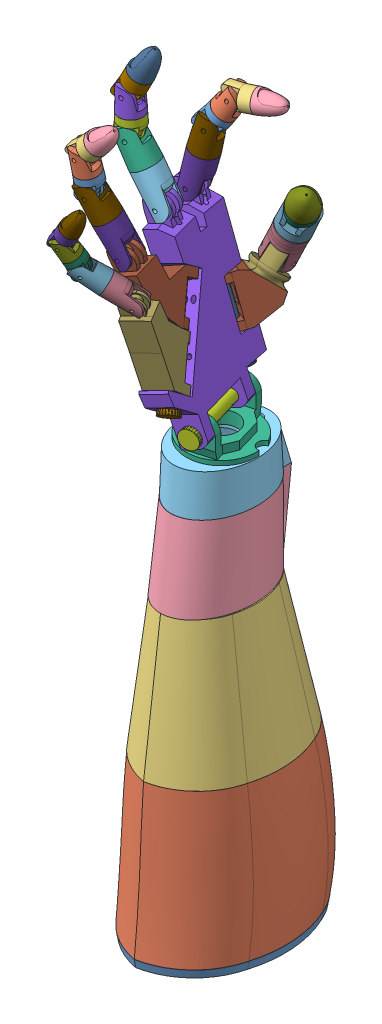
SolidWorks assembly brat bionic_DESEN, configuration Default. Lengths in mm.
Overall size (133.2 492.97 178.43).
47 component instances, 36 part files, 46 mates.
Components (placement in the parent):
- capac-1: capac [Default] x (0 0 1) z (0 -1 0) size (118 85.51 15.8)
- brat-1: brat [Default] at (21.3792 100.51 -54.6588) x (0 0 1) z (0 1 0) size (122.64 91.01 100.55)
- brat3-1: brat3 [Default] at (23.3637 100.51 -0.673) x (0 0 1) z (0 1 0) size (108.18 78.67 92.99)
- rotatie3-1: rotatie3 [Default] at (21.3637 247.6 0.827) x (0 -1 0) z (0 0 -1) size (54.52 53.72 79.07)
- rotatie2-1: rotatie2 [Default] at (21.3637 275.1 2.3667) x (0 0 1) z (0 1 0) size (71.08 50.43 27.52)
- rotatie-1: rotatie [Default] at (21.3637 275.1 0.7767) x (0 1 0) z (-0.279713 0 -0.960084) size (25.5 46.57 47)
- kama3-1: kama3 [Default] at (15.0338 293.6 -20.95) x (0.279713 0 0.960084) z (0.277949 0.957176 -0.080978) size (55.22 12.11 12.06)
- incheietura-1: incheietura [Default] at (-2.942 339.9019 9.4591) x (0.279713 0 0.960084) z (0.902971 0.339759 -0.263073) size (89.87 119.48 17.05)
- kama1-1: kama1 [Default] at (-8.0769 369.6087 -2.1099) x (0.429618 -0.725931 0.537078) z (-0.595277 0.219563 0.772941) size (81.63 11.99 11.99)
- kama2-1: kama2 [Default] at (-9.1071 355.492 -23.8777) x (0.348299 -0.937264 -0.014976) z (-0.570869 -0.224759 0.789679) size (58.94 11.99 11.99)
- deget 1-1: deget 1 [Default] at (-3.3392 333.1412 -37.1218) x (-0.348299 0.937264 0.014976) z (0.814841 0.29483 0.499108) size (30.12 34.69 17)
- deget mare-2: deget mare [Default] at (7.4685 341.2427 -42.0206) x (-0.567496 0.581345 0.583083) z (-0.118243 -0.758362 0.641019) size (43.45 64.19 58.55)
  - deget3-1: deget3 [Default] at origin size (24.28 22.96 17.51)
  - deget 2-1: deget 2 [Default] at (5.185 -11.6868 -28.9168) x (-0.905973 -0.423336 0) z (-0.262459 0.561682 0.78462) size (20 20 23)
  - deget-1: deget [Default] at (9.1429 -20.157 -40.7488) x (-0.262459 0.561682 0.78462) z (0.332158 -0.710844 0.619977) size (15.08 20.32 19.9)
  - Thump50-1: Thump50 [Default] at (12.6343 -27.6289 -42.1434) x (-0.167923 0.359369 -0.917963) z (-0.388607 0.831649 0.396666) size (19.12 18.1 18.16)
  - deget4-1: deget4 [Default] at (12.6343 -27.6289 -42.1434) x (0.905973 0.423336 0) z (-0.167923 0.359369 -0.917963) size (18 20.37 18.06)
- deget ia montaj-1: deget ia montaj [Default] at (-17.3564 410.2511 -26.3348) x (0.955402 -0.189315 -0.226645) z (0.246879 0.090894 0.964774) size (48.75 80.18 17)
  - deget ia 3-4-1: deget ia 3-4 [Default] x (0 0 -1) z (-1 0 0) size (17 27 17)
  - deget ia 3-3-1: deget ia 3-3 [Default] x (0 -1 0) z (-1 0 0) size (22 17 17)
  - deget ia 3-5-1: deget ia 3-5 [Default] at (4.5856 26.5941 0) x (-0.379027 -0.925386 0) z (0 0 -1) size (17.26 16.52 15.41)
  - deget ia 3-6-1: deget ia 3-6 [Default] at (10.6501 41.4003 0) x (-0.379027 -0.925386 0) z (0.925386 -0.379027 0) size (16 15.32 14.93)
  - deget ia 3-2-1: deget ia 3-2 [Default] at (20.2707 40.9559 0) x (-0.328897 0.944366 0) z (-0.944366 -0.328897 0) size (14.75 14.1 18.07)
  - deget ia-1: deget ia [Default] at (20.2694 40.9597 0) x (0 0 1) z (-0.328897 0.944366 0) size (14.02 17.03 14.02)
- deget mijlociu-1: deget mijlociu [Default] at (-24.9915 413.925 5.087) x (0.476461 -0.871782 -0.113937) z (-0.83615 -0.489365 0.247741) size (91.07 17.94 51.58)
  - major3-4-1: major3-4 [Default] x (0 -1 0) z (0 0 1) size (17.93 28.49 17.93)
  - major3-3-1: major3-3 [Default] at origin size (23.21 17.94 17.94)
  - major3-5-1: major3-5 [Default] at (-27.6629 0 -5.8011) x (0.89116 0 0.453688) z (0 -1 0) size (18.44 17.85 16.26)
  - major3-6-1: major3-6 [Default] at (-42.7057 0 -13.4594) x (0.89116 0 0.453688) z (0.453688 0 -0.89116) size (16.88 16.16 15.75)
  - major3-2-1: major3-2 [Default] at (-46.0011 0 -21.6092) x (-0.814988 0 0.579478) z (0.579478 0 0.814988) size (15.56 14.88 19.06)
  - articulatiemijlociu3-1: articulatiemijlociu3 [Default] at (-46.0046 0 -21.6067) x (0 1 0) z (-0.814988 0 0.579478) size (14.79 18.22 14.79)
- incheietura_-1: incheietura_ [Default] at (-2.9717 348.2192 28.4926) x (-0.206102 0.154463 -0.966262) z (0.890728 0.438436 -0.119904) size (37.9 57.51 17.01)
- incheietura2-1: incheietura2 [Default] at (20.6473 360.445 35.269) x (0.399816 0.042041 0.915631) z (-0.887777 -0.230758 0.398249) size (41.78 67.66 17.05)
- articulatie3 montaj-1: articulatie3 montaj [Default] at (2.8426 385.5559 59.6911) x (0.710642 -0.509774 -0.48489) z (-0.545039 -0.834704 0.078746) size (60.35 14.17 42.86)
  - articulatie3-4-1: articulatie3-4 [Default] x (0 -1 0) z (0 0 1) size (14.17 22.51 14.17)
  - articulatie3-3-1: articulatie3-3 [Default] at origin size (18.34 14.17 14.17)
  - articulatie3-5-1: articulatie3-5 [Default] at (-21.6619 0 -4.9815) x (0.870233 0 0.492641) z (0 -1 0) size (14.57 13.77 12.85)
  - articulatie3-6-1: articulatie3-6 [Default] at (-33.2674 0 -11.5513) x (0.870233 0 0.492641) z (0.492641 0 -0.870233) size (13.34 12.77 12.44)
  - articulatie3-2-2: articulatie3-2 [Default] at (-30.6723 0 -19.5986) x (-0.99542 0 0.095597) z (0.095597 0 0.99542) size (12.3 11.75 15.1)
  - articulatie3-1: articulatie3 [Default] at (-30.6757 0 -19.5983) x (0 1 0) z (-0.99542 0 0.095597) size (11.69 14.19 11.69)
- deget ia montaj-2: deget ia montaj [Default] at (-18.6487 402.3542 37.5434) x (0.869334 0.481879 -0.109776) z (0.195105 -0.130536 0.972057) size (48.75 80.18 17)
  - deget ia 3-4-1: deget ia 3-4 [Default] x (0 0 -1) z (-1 0 0) size (17 27 17)
  - deget ia 3-3-1: deget ia 3-3 [Default] x (0 -1 0) z (-1 0 0) size (22 17 17)
  - deget ia 3-5-1: deget ia 3-5 [Default] at (4.5856 26.5941 0) x (-0.379027 -0.925386 0) z (0 0 -1) size (17.26 16.52 15.41)
  - deget ia 3-6-1: deget ia 3-6 [Default] at (10.6501 41.4003 0) x (-0.379027 -0.925386 0) z (0.925386 -0.379027 0) size (16 15.32 14.93)
  - deget ia 3-2-1: deget ia 3-2 [Default] at (20.2707 40.9559 0) x (-0.328897 0.944366 0) z (-0.944366 -0.328897 0) size (14.75 14.1 18.07)
  - deget ia-1: deget ia [Default] at (20.2694 40.9597 0) x (0 0 1) z (-0.328897 0.944366 0) size (14.02 17.03 14.02)
Mates (geometry in assembly coordinates):
- Coincident1: coincident anti-aligned: plane of capac-1 through (0 0 0) normal (0 -1 0)
- Coincident2: coincident anti-aligned: plane of capac-1 through (0 0 0) normal (-1 0 0)
- Coincident3: coincident aligned: plane of capac-1 through (0 0 0) normal (0 0 1)
- Concentric8: concentric aligned: circle of capac-1; circle of brat-1
- Coincident4: coincident anti-aligned: plane of capac-1 through (27.0674 0 -14.9828) normal (0 1 0); plane of brat-1 through (12.3179 0 10.0833) normal (0 -1 0)
- Parallel1: parallel aligned: plane of brat-1 through (21.3792 100.51 -54.6588) normal (1 0 0)
- Concentric10: concentric aligned: circle of brat-1; circle of brat3-1
- Coincident5: coincident anti-aligned: plane of brat-1 through (16.2073 100.51 -14.3784) normal (0 1 0); plane of brat3-1 through (15.3542 100.51 -13.3417) normal (0 -1 0)
- Parallel2: parallel aligned: plane of brat-1 through (21.3792 100.51 -54.6588) normal (1 0 0); plane of brat3-1 through (23.3637 100.51 -0.673) normal (1 0 0)
- Distance5: distance = 2 mm anti-aligned: plane of brat3-1 through (23.3637 100.51 -0.673) normal (1 0 0); plane of rotatie3-1 through (21.3637 247.6 0.827) normal (-1 0 0)
- Coincident7: coincident anti-aligned: plane of brat3-1 through (17.2122 193.1 -4.2925) normal (0 1 0); plane of rotatie3-1 through (21.3637 193.1 4.397) normal (0 -1 0)
- Distance6: distance = 1.5 mm anti-aligned: plane of rotatie3-1 through (21.3637 247.6 0.827) normal (0 0 -1); plane of brat3-1 through (23.3637 100.51 -0.673) normal (0 0 1)
- Coincident9: coincident anti-aligned: plane of rotatie3-1 through (21.3637 247.6 0.827) normal (0 1 0); plane of rotatie2-1 through (21.4437 247.6 0.7167) normal (0 -1 0)
- Coincident10: coincident anti-aligned: line of rotatie3-1 through (10.5337 247.6 -35.6949) axis (1 0 0); line of rotatie2-1 through (32.1137 247.6 -35.6949) axis (-1 0 0)
- Coincident12: coincident anti-aligned: plane of rotatie3-1 through (21.3637 247.6 0.827) normal (-1 0 0); plane of rotatie2-1 through (21.3637 275.1 2.3667) normal (1 0 0)
- Concentric11: concentric anti-aligned: cylinder of rotatie2-1; cylinder of rotatie-1 through (21.3637 278.1 0.7767) axis (0 -1 0) radius 10.75
- Coincident14: coincident anti-aligned: plane of rotatie2-1 through (21.3637 275.1 0.7767) normal (0 1 0); plane of rotatie-1 through (32.6447 275.1 -2.5099) normal (0 -1 0)
- Concentric12: concentric aligned: cylinder of rotatie-1 through (30.8582 293.6 33.3655) axis (-0.279713 0 -0.960084) radius 4; cylinder of kama3-1 through (29.6181 293.6 29.1088) axis (-0.279713 0 -0.960084) radius 4
- Coincident15: coincident anti-aligned: circle of kama3-1; plane of rotatie-1 through (23.9962 300.6 -23.5611) normal (-0.279713 0 -0.960084)
- Concentric13: concentric aligned: cylinder of kama3-1 through (29.6181 293.6 29.1088) axis (-0.279713 0 -0.960084) radius 4; cylinder of incheietura-1 through (32.7826 293.6 39.9709) axis (-0.279713 0 -0.960084) radius 4
- Coincident16: coincident anti-aligned: plane of rotatie-1 through (36.656 300.6 19.8923) normal (0.279713 0 0.960084); plane of incheietura-1 through (32.3055 305.3204 21.1598) normal (-0.279713 0 -0.960084)
- LimitAngle2: limit planar angle = 0.444162 rad aligned: plane of incheietura-1 through (-2.942 339.9019 9.4591) normal (0.902971 0.339759 -0.263073)
- Concentric14: concentric anti-aligned: cylinder of incheietura-1 through (-8.3833 370.1265 -2.493) axis (0.429618 -0.725931 0.537078) radius 4; cylinder of kama1-1 through (25.704 312.5287 40.1205) axis (-0.429618 0.725931 -0.537078) radius 4
- Coincident17: coincident anti-aligned: plane of incheietura-1 through (33.2749 308.0741 28.0434) normal (0.429618 -0.725931 0.537078); plane of kama1-1 through (25.704 312.5287 40.1205) normal (-0.429618 0.725931 -0.537078)
- Concentric15: concentric anti-aligned: cylinder of incheietura-1 through (-9.0861 355.4355 -23.8786) axis (0.348299 -0.937264 -0.014976) radius 4; cylinder of kama2-1 through (10.3768 303.0614 -24.7154) axis (-0.348299 0.937264 0.014976) radius 4
- Coincident18: coincident anti-aligned: plane of incheietura-1 through (15.8878 305.2777 -35.2476) normal (0.348299 -0.937264 -0.014976); plane of kama2-1 through (10.3768 303.0614 -24.7154) normal (-0.348299 0.937264 0.014976)
- Concentric16: concentric aligned: cylinder of kama2-1 through (10.3768 303.0614 -24.7154) axis (-0.348299 0.937264 0.014976) radius 4; cylinder of deget 1-1 through (6.4434 313.6459 -24.5463) axis (-0.348299 0.937264 0.014976) radius 4
- Symmetric1: symmetric aligned: plane of deget 1-1 through (5.1437 350.6115 -27.23) normal (-0.348299 0.937264 0.014976); plane of deget 1-1 through (8.683 319.5923 -14.6849) normal (0.348299 -0.937264 -0.014976)
- Coincident20: coincident anti-aligned: plane of deget 1-1 through (20.7171 336.9896 -44.6084) normal (0.118243 0.758362 -0.641019); plane of deget mare-2/deget3-1 through (7.4685 341.2427 -42.0206) normal (-0.118243 -0.758362 0.641019)
- Coincident21: coincident aligned: line of deget 1-1 through (20.7171 336.9896 -44.6084) axis (-0.567496 0.581345 0.583083); line of deget mare-2/deget3-1 through (20.7171 336.9896 -44.6084) axis (-0.567496 0.581345 0.583083)
- Coincident22: coincident anti-aligned: line of deget 1-1 through (20.7171 336.9896 -44.6084) axis (-0.814841 -0.29483 -0.499108); line of deget mare-2/deget3-1 through (6.8648 331.9774 -53.0933) axis (0.814841 0.29483 0.499108)
- Concentric17: concentric anti-aligned: cylinder of incheietura-1 through (-1.2977 397.8308 55.7071) axis (-0.246879 -0.090894 -0.964774) radius 1.25; cylinder of deget ia montaj-1/deget ia 3-4-1 through (-28.2044 387.9246 -49.4412) axis (0.246879 0.090894 0.964774) radius 1.25
- Coincident23: coincident anti-aligned: plane of incheietura-1 through (-17.1844 397.3683 -29.8294) normal (-0.246879 -0.090894 -0.964774); plane of deget ia montaj-1/deget ia 3-4-1 through (-10.3454 408.2327 -32.603) normal (0.246879 0.090894 0.964774)
- Concentric18: concentric aligned: cylinder of incheietura-1 through (-14.1898 394.7138 7.4306) axis (0.271733 0.02277 0.962103) radius 1.25; cylinder of deget mijlociu-1/major3-4-1 through (-23.2215 393.957 -24.5473) axis (0.271733 0.02277 0.962103) radius 1.3188
- Coincident24: coincident anti-aligned: plane of incheietura-1 through (-11.2119 401.9167 -3.4551) normal (-0.271733 -0.02277 -0.962103); plane of deget mijlociu-1/major3-4-1 through (-18.7825 418.2058 -1.7024) normal (0.271733 0.02277 0.962103)
- Coincident25: coincident anti-aligned: plane of incheietura-1 through (3.5372 362.1672 -4.1671) normal (0.429618 -0.725931 0.537078); plane of incheietura_-1 through (1.4862 373.7264 13.0973) normal (-0.429618 0.725931 -0.537078)
- Concentric19: concentric aligned: cylinder of kama1-1 through (25.704 312.5287 40.1205) axis (-0.429618 0.725931 -0.537078) radius 4; cylinder of incheietura_-1 through (13.9737 332.3495 25.4562) axis (-0.429618 0.725931 -0.537078) radius 4
- Concentric20: concentric anti-aligned: cylinder of kama1-1 through (25.704 312.5287 40.1205) axis (-0.429618 0.725931 -0.537078) radius 4; cylinder of incheietura2-1 through (5.3645 346.8967 14.6935) axis (0.429618 -0.725931 0.537078) radius 4
- Coincident26: coincident anti-aligned: plane of incheietura-1 through (30.3444 329.1909 45.2571) normal (-0.429618 0.725931 -0.537078); plane of incheietura2-1 through (17.3204 324.988 49.9945) normal (0.429618 -0.725931 0.537078)
- Concentric21: concentric aligned: cylinder of incheietura2-1 through (11.6796 377.5753 45.794) axis (0.444882 -0.208324 0.871023) radius 1.25; cylinder of articulatie3 montaj-1/articulatie3-4-1 through (4.5642 380.9072 31.8631) axis (0.444882 -0.208324 0.871023) radius 1.0419
- Coincident27: coincident anti-aligned: plane of incheietura2-1 through (5.8488 368.8993 49.8657) normal (-0.444882 0.208324 -0.871023); plane of articulatie3 montaj-1/articulatie3-4-1 through (21.5557 380.4013 44.5943) normal (0.444882 -0.208324 0.871023)
- Concentric22: concentric aligned: cylinder of incheietura_-1 through (-9.2644 383.5835 37.6657) axis (0.195105 -0.130536 0.972057) radius 1.25; cylinder of deget ia montaj-2/deget ia 3-4-1 through (-15.3907 387.6823 7.1431) axis (0.195105 -0.130536 0.972057) radius 1.25
- Coincident28: coincident anti-aligned: plane of incheietura_-1 through (11.0337 356.4333 20.7898) normal (-0.195105 0.130536 -0.972057); plane of deget ia montaj-2/deget ia 3-4-1 through (-12.1365 407.0381 32.2359) normal (0.195105 -0.130536 0.972057)
- LimitAngle3: limit planar angle = 0.174533 rad: plane of assembly through (107.3087 40.3768 -31.2635) normal (0.902971 0.339759 -0.263073); plane of assembly; plane of incheietura_-1 through (-2.9717 348.2192 28.4926) normal (0.890728 0.438436 -0.119904)
- LimitAngle4: limit planar angle = 0.174533 rad: plane of assembly through (107.3087 40.3768 -31.2635) normal (0.902971 0.339759 -0.263073); plane of assembly; plane of incheietura2-1 through (20.6473 360.445 35.269) normal (-0.887777 -0.230758 0.398249)
- LimitAngle5: limit planar angle = 0.785398 rad: plane of assembly through (3.5663 0 12.2411) normal (0.279713 0 0.960084); plane of assembly; plane of deget 1-1 through (-3.3392 333.1412 -37.1218) normal (0.814841 0.29483 0.499108)
